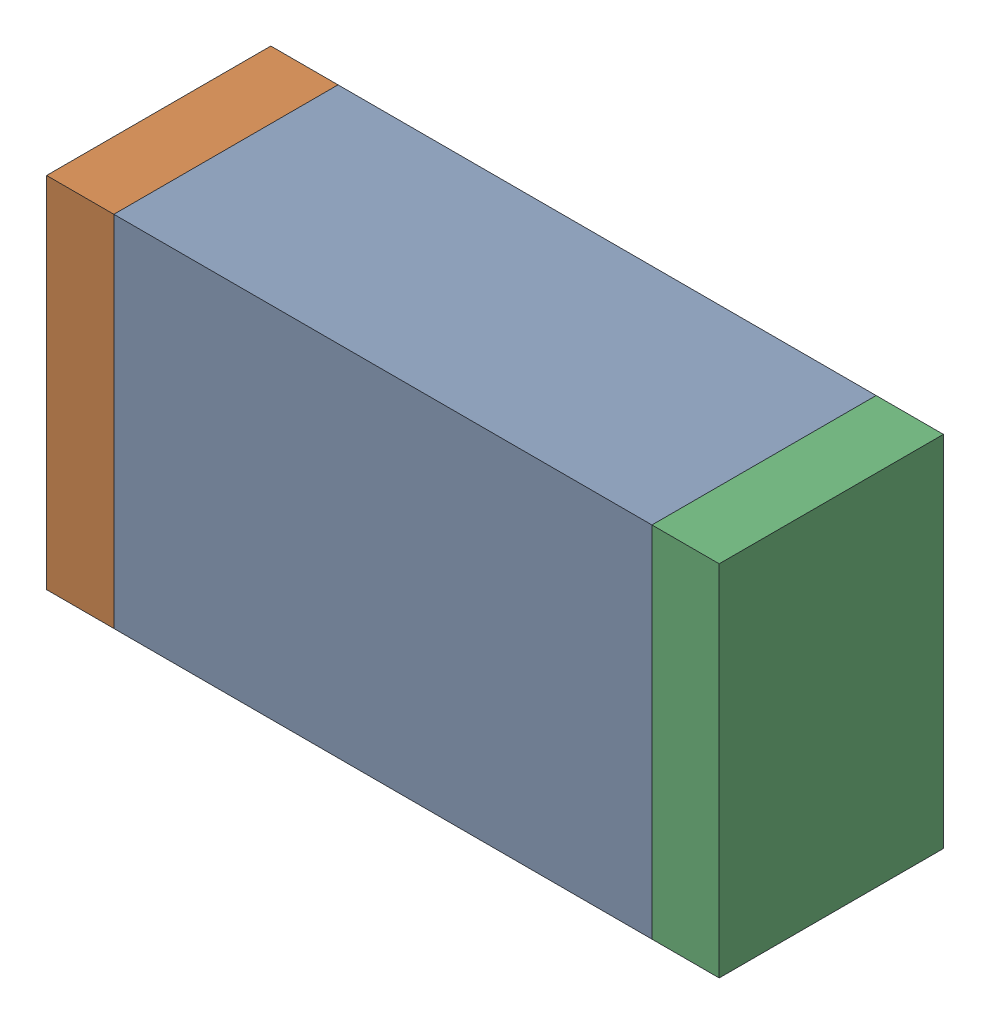
SolidWorks assembly R71, configuration Default. Lengths in mm.
Overall size (1.5 0.8 0.5).
6 component instances, 2 part files, 0 mates.
Components (placement in the parent):
- 836752368-1: 836752368 [Default] at (100.65 80.2 0) size (1.2 0.8 0.5)
  - Extruded-1: Extruded [Default] at origin size (1.2 0.8 0.5)
- 836752496-1: 836752496 [Default] at (99.975 80.2 0) size (0.15 0.8 0.5)
  - Extruded_2-1: Extruded_2 [Default] at origin size (0.15 0.8 0.5)
- 836752496-2: 836752496 [Default] at (101.325 80.2 0) size (0.15 0.8 0.5)
  - Extruded_2-1: Extruded_2 [Default] at origin size (0.15 0.8 0.5)
